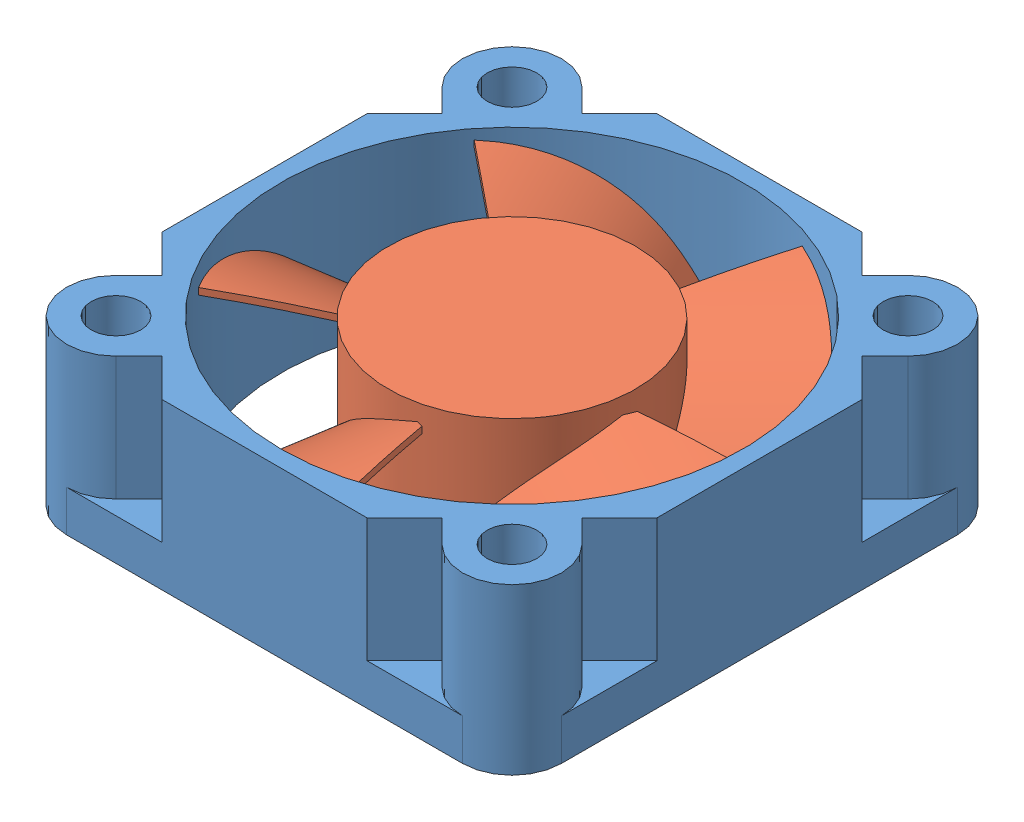
SolidWorks assembly Fan 3010, configuration Default. Lengths in mm.
Overall size (38.06 10.51 38.06).
2 component instances, 2 part files, 2 mates.
Components (placement in the parent):
- Fan Casca-1: Fan Casca [Default] at (-72.4601 -2.5046 36.5408) size (30 10 30)
- Fan Helices-1: Fan Helices [Default] at (-72.4601 -1.9046 36.5408) x (0.562267 0 -0.826955) z (0.826955 0 0.562267) size (27.4 10.25 27.4)
Mates (geometry in assembly coordinates):
- Concentric1: concentric anti-aligned: cylinder of Fan Casca-1 through (-72.4601 -2.0046 36.5408) axis (0 1 0) radius 14; cylinder of Fan Helices-1 through (-72.4601 7.3954 36.5408) axis (0 -1 0) radius 7.5
- Coincident1: coincident anti-aligned: plane of Fan Casca-1 through (-72.4601 5.4954 36.5408) normal (0 1 0); plane of Fan Helices-1 through (-72.4601 5.4954 36.5408) normal (0 -1 0)
